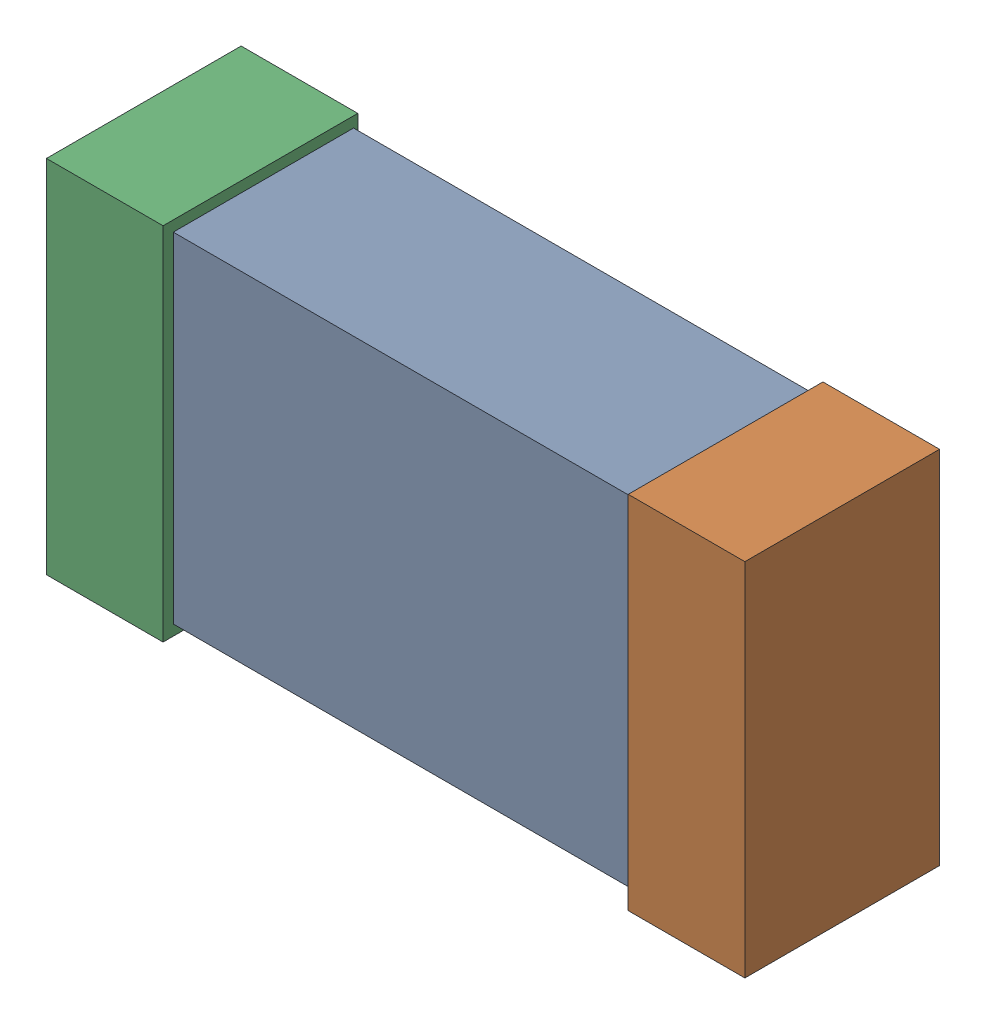
SolidWorks assembly R21, configuration Default. Lengths in mm.
Overall size (1.65 0.85 0.46).
6 component instances, 2 part files, 0 mates.
Components (placement in the parent):
- 432120720_4-1: 432120720_4 [Default] at (18.2499 35.0001 -0.8615) size (1.5 0.8 0.42)
  - Extruded (12)-1: Extruded (12) [Default] at origin size (1.5 0.8 0.42)
- 432120464_8-1: 432120464_8 [Default] at (18.9357 35.0001 -0.8715) size (0.28 0.85 0.46)
  - Extruded (11)-1: Extruded (11) [Default] at origin size (0.28 0.85 0.46)
- 432120464_9-1: 432120464_9 [Default] at (17.5642 35.0001 -0.8715) size (0.28 0.85 0.46)
  - Extruded (11)-1: Extruded (11) [Default] at origin size (0.28 0.85 0.46)
